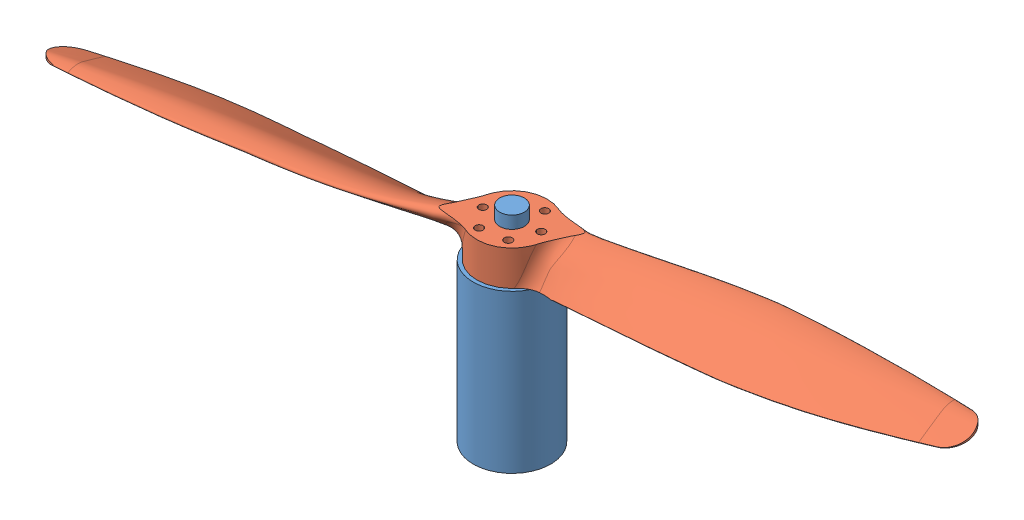
SolidWorks assembly motorsym, configuration Default. Lengths in mm.
Overall size (950.73 131.02 344.34).
2 component instances, 2 part files, 2 mates.
Components (placement in the parent):
- motor-1: motor [Default] at (56.1749 10 -15.5304) x (-0.204409 0 -0.978885) z (0.978885 0 -0.204409) size (4.92 13 4.92)
- propeller-1: propeller [Default] at (54.4283 1.9853 -17.262) x (0.987389 0 -0.158315) z (0.158315 0 0.987389) size (939.94 131.02 198.03)
Mates (geometry in assembly coordinates):
- Concentric3: concentric: cylinder of motor-1 through (54.4249 13 -17.2613) axis (0 -1 0) radius 0.78; cylinder of propeller-1 through (54.4249 12.9418 -17.2613) axis (0 1 0) radius 0.7814
- Coincident3: coincident: plane of motor-1 through (54.4249 10 -17.2613) normal (0 1 0); plane of propeller-1 through (54.4249 10 -17.2613) normal (0 -1 0)
